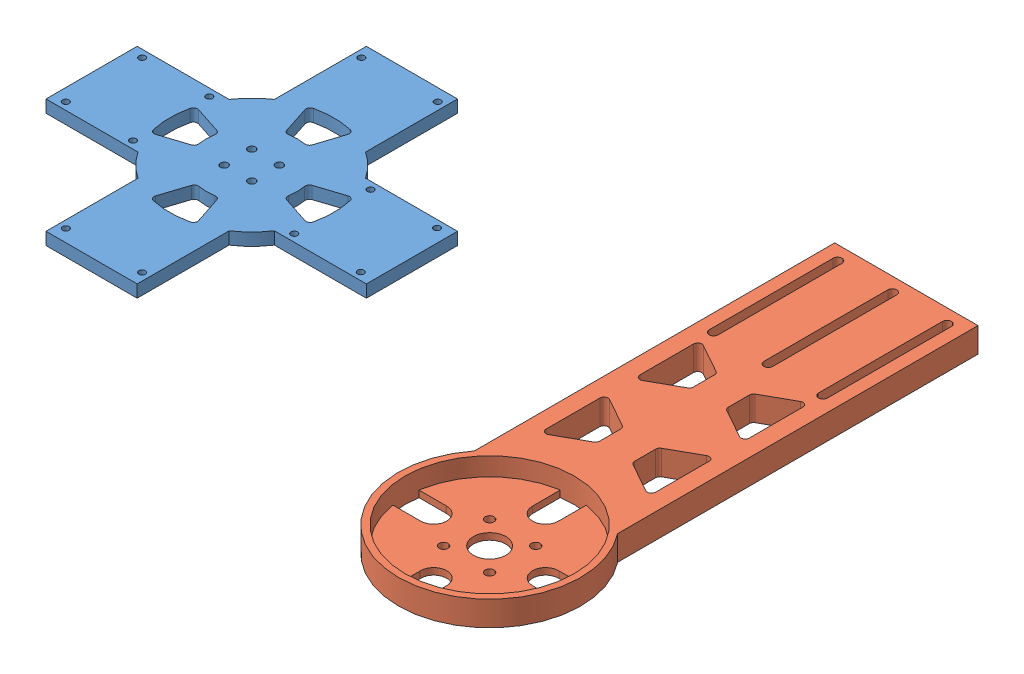
SolidWorks assembly Yaw and handle mount, configuration Default. Lengths in mm.
Overall size (261.76 9.53 195).
2 component instances, 2 part files, 0 mates.
Components (placement in the parent):
- Handle Mount-1: Handle Mount [Default] at (-35.5751 120.8855 6.296) size (123 4.76 123)
- Yaw Arm-1: Yaw Arm [Default] at (129.6824 116.123 80.235) size (70 9.53 195)
